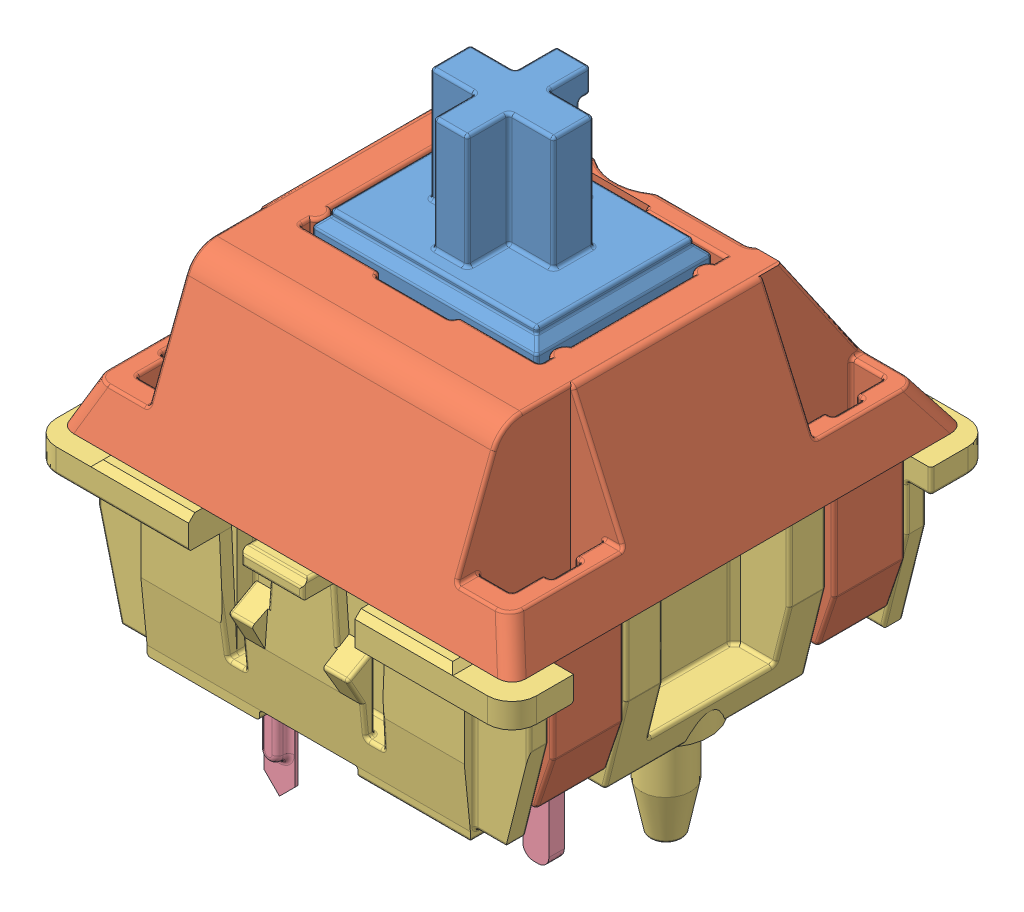
SolidWorks assembly Switch, configuration Default. Lengths in mm.
Overall size (15.6 18.6 15.6).
4 component instances, 4 part files, 6 mates.
Components (placement in the parent):
- NAF_MX 轴 按键-1: NAF_MX 轴 按键 [Default] at (7.35 2 -7.35) size (8.9 10.4 5.7)
- NAF_MX 轴 轴体-1: NAF_MX 轴 轴体 [Default] at origin size (14.7 9.91 14.7)
- NAF_MX轴 轴体 底部-1: NAF_MX轴 轴体 底部 [默认] at (7.35 -0.2 -7.35) size (15.6 12.5 15.6)
- NAF_针脚-2: NAF_针脚 [默认] at (-5.5727 -8.7 12.741) size (7.15 6.7 2.96)
Mates (geometry in assembly coordinates):
- Distance1: distance = 0.15 mm anti-aligned: plane of NAF_MX 轴 轴体-1 through (3.45 1.4 -4.35) normal (0 0 -1); plane of NAF_MX 轴 按键-1 through (3.7 5.2 -4.5) normal (0 0 1)
- Distance2: distance = 0.25 mm anti-aligned: plane of NAF_MX 轴 轴体-1 through (3.45 1.4 -10.35) normal (1 0 0); plane of NAF_MX 轴 按键-1 through (3.7 5.2 -10.2) normal (-1 0 0)
- Coincident4: coincident anti-aligned: plane of NAF_MX 轴 轴体-1 through (0 0 0) normal (0 -1 0); plane of NAF_MX轴 轴体 底部-1 through (7.35 0 -7.35) normal (0 1 0)
- LimitDistance2: limit distance = -0.5 mm aligned: plane of NAF_MX 轴 按键-1 through (7.35 5.7 -7.35) normal (0 1 0); plane of NAF_MX 轴 轴体-1 through (0 5.2 0) normal (0 1 0)
- Coincident10: coincident anti-aligned: plane of NAF_MX轴 轴体 底部-1 through (10.6 -0.9 -4.95) normal (0 0 1); plane of NAF_针脚-2 through (10.6 -2.5 -4.95) normal (0 0 -1)
- Coincident11: coincident anti-aligned: plane of NAF_MX轴 轴体 底部-1 through (10.6 -0.9 -4.95) normal (1 0 0); plane of NAF_针脚-2 through (10.6 -2.5 -4.95) normal (-1 0 0)
